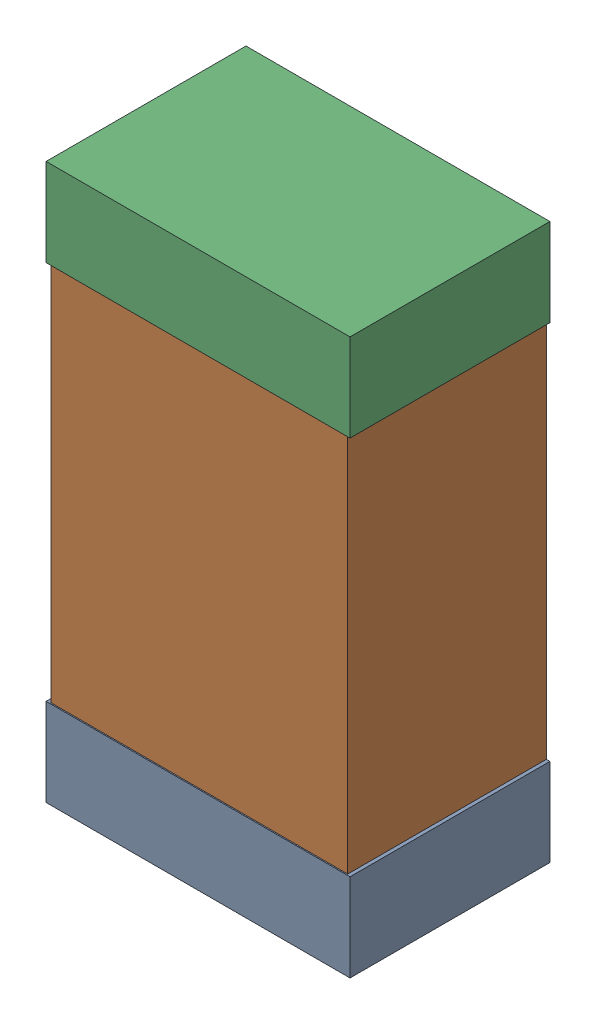
SolidWorks assembly C24Kanaloa_v2.0.0_Power, configuration Default. Lengths in mm.
Overall size (1.3 2.38 0.85).
6 component instances, 2 part files, 0 mates.
Components (placement in the parent):
- 330415056-1: 330415056 [Default] at (50.038 160.036 0) size (1.3 0.38 0.85)
  - Extruded_2-1: Extruded_2 [Default] at origin size (1.3 0.38 0.85)
- 352877008-1: 352877008 [Default] at (50.038 161.036 0) size (1.27 2.2 0.85)
  - Extruded_3-1: Extruded_3 [Default] at origin size (1.27 2.2 0.85)
- 330415056-2: 330415056 [Default] at (50.038 162.036 0) size (1.3 0.38 0.85)
  - Extruded_2-1: Extruded_2 [Default] at origin size (1.3 0.38 0.85)
